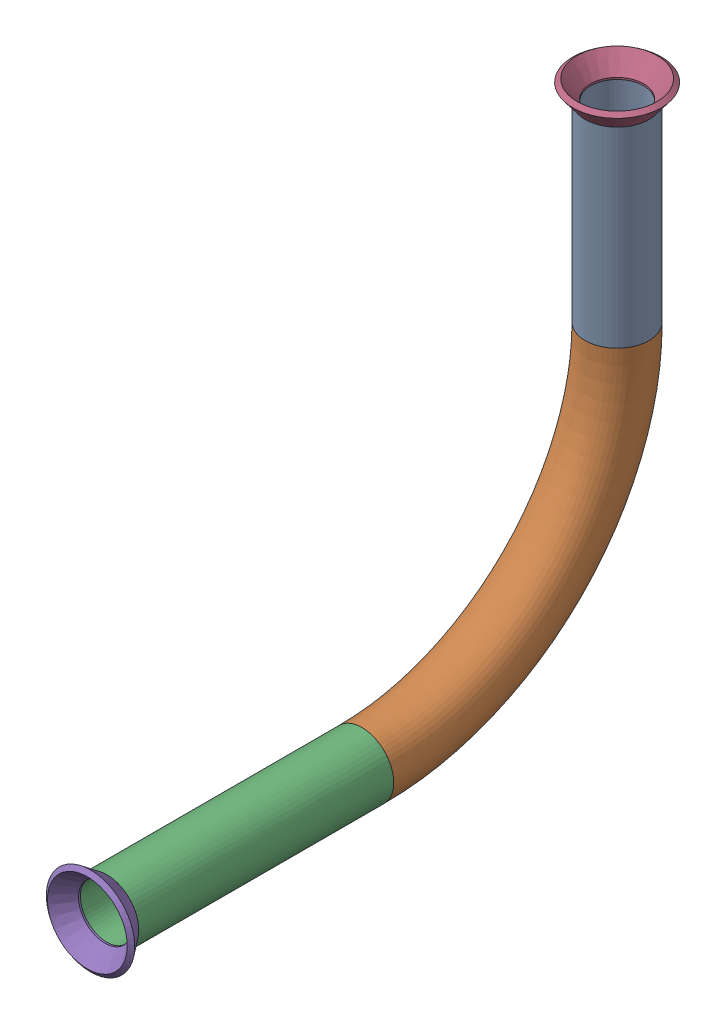
SolidWorks assembly Pipe 10, configuration Default. Lengths in mm.
Overall size (17.59 101.58 114.23).
3 component instances, 2 part files, 4 mates.
Components (placement in the parent):
- Part1-1: Part1 [Default<As Machined>] at origin size (12.7 95.25 107.9)
- Flared pipe end - .5 inch-1: Flared pipe end - .5 inch [Default<As Machined>] at (0 -187.6805 259.1796) x (1 0 0.00017) z (0 1 0) size (17.59 17.59 3.89)
- Flared pipe end - .5 inch-2: Flared pipe end - .5 inch [Default<As Machined>] at (0 -276.5805 360.7276) x (1 -0.00017 0) z (0 0 1) size (17.59 17.59 3.89)
Mates (geometry in assembly coordinates):
- Coincident1032: coincident: plane of Part1-1 through (0 -187.6805 259.1796) normal (0 1 0); plane of Flared pipe end - .5 inch-1 through (0.0009 -187.6805 253.8964) normal (0 -1 0)
- Concentric658: concentric: circle of Part1-1; circle of Flared pipe end - .5 inch-1
- Coincident1033: coincident: plane of Part1-1 through (0 -276.5805 360.7276) normal (0 0 1); plane of Flared pipe end - .5 inch-2 through (0.0009 -271.2973 360.7276) normal (0 0 -1)
- Concentric659: concentric: circle of Part1-1; circle of Flared pipe end - .5 inch-2
